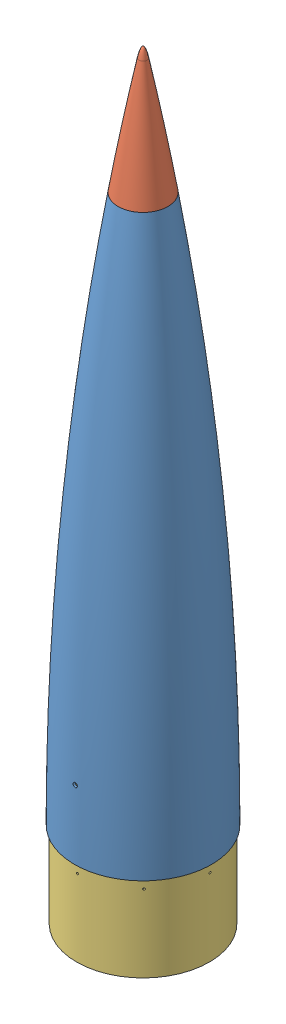
SolidWorks assembly Nosecone, configuration Default. Lengths in mm.
Overall size (203.2 1127.33 203.2).
3 component instances, 3 part files, 4 mates.
Components (placement in the parent):
- Tangent_Ogive_Nosecone_nocoupler-1: Tangent_Ogive_Nosecone_nocoupler [40in] at origin size (203.2 812.8 203.2)
- Tangent_Ogive_Nosecone_Tip-1: Tangent_Ogive_Nosecone_Tip [40in] x (0.411492 0 -0.911413) z (0.911413 0 0.411492) size (73.62 187.53 73.62)
- Nosecone_Coupler-1: Nosecone_Coupler [40in] at (0 88.9 0) x (0.999944 0 -0.010556) z (0.010556 0 0.999944) size (196.85 215.9 196.85)
Mates (geometry in assembly coordinates):
- Coincident1: coincident anti-aligned: plane of Tangent_Ogive_Nosecone_nocoupler-1 through (0 812.8 0) normal (0 1 0); plane of Tangent_Ogive_Nosecone_Tip-1 through (0 812.8 0) normal (0 -1 0)
- Coincident2: coincident anti-aligned: circle of Tangent_Ogive_Nosecone_nocoupler-1; circle of Tangent_Ogive_Nosecone_Tip-1
- Concentric1: concentric aligned: cylinder of Tangent_Ogive_Nosecone_nocoupler-1; cylinder of Nosecone_Coupler-1 through (0 88.9 0) axis (0 -1 0) radius 98.425
- Distance1: distance = 88.9 mm anti-aligned: plane of Tangent_Ogive_Nosecone_nocoupler-1 through (0 0 0) normal (0 -1 0); plane of Nosecone_Coupler-1 through (-146.9555 88.9 -100.0543) normal (0 1 0)
